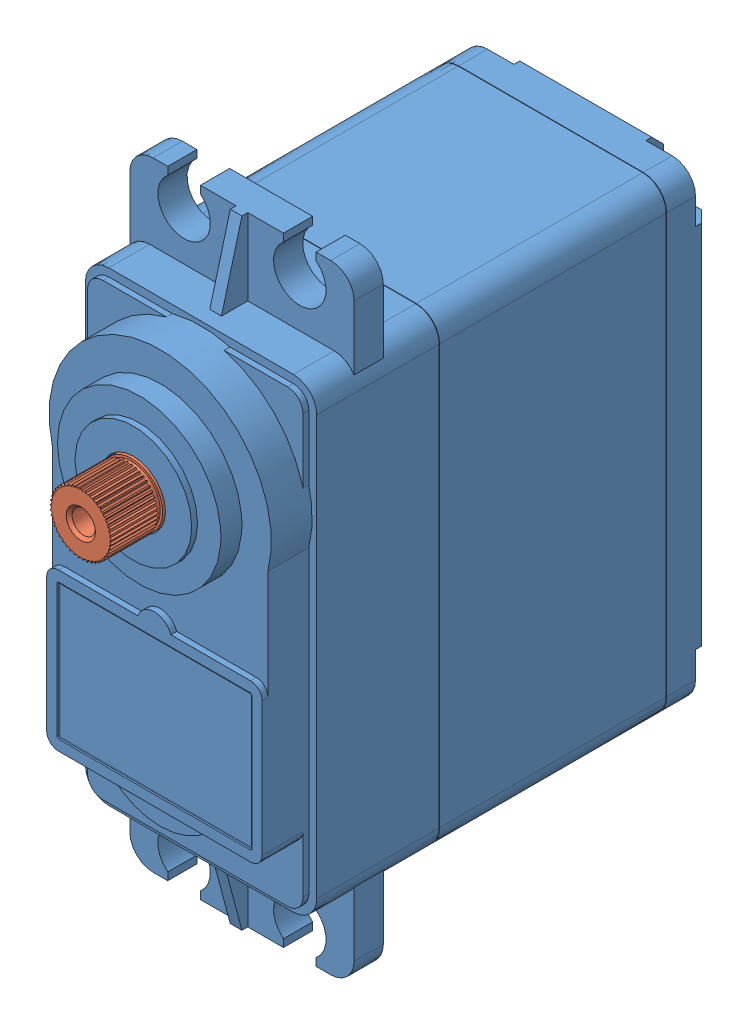
SolidWorks assembly SERVO, configuration Default. Lengths in mm.
Overall size (19.81 52.98 44.24).
2 component instances, 2 part files, 2 mates.
Components (placement in the parent):
- SERVOMOTORE Hitec HS485-HB-1: SERVOMOTORE Hitec HS485-HB [Default] at (-48.0481 -59.6098 -19.87) size (19.81 52.98 39.74)
- Ingranaggio dentato innesto servomotore-1: Ingranaggio dentato innesto servomotore [Default] at (-6.2498 9.8954 17.87) x (1 0 0) z (0 -1 0) size (5.3 6.5 5.3)
Mates (geometry in assembly coordinates):
- Coincidente1: coincident anti-aligned: plane of SERVOMOTORE Hitec HS485-HB-1 through (-6.2498 9.8954 17.87) normal (0 0 1); plane of Ingranaggio dentato innesto servomotore-1 through (-6.2498 9.8954 17.87) normal (0 0 -1)
- Concentrico1: concentric anti-aligned: cylinder of SERVOMOTORE Hitec HS485-HB-1 through (-6.2498 9.8954 17.87) axis (0 0 1) radius 2.75; cylinder of Ingranaggio dentato innesto servomotore-1 through (-6.2498 9.8954 20.02) axis (0 0 -1) radius 2.65
